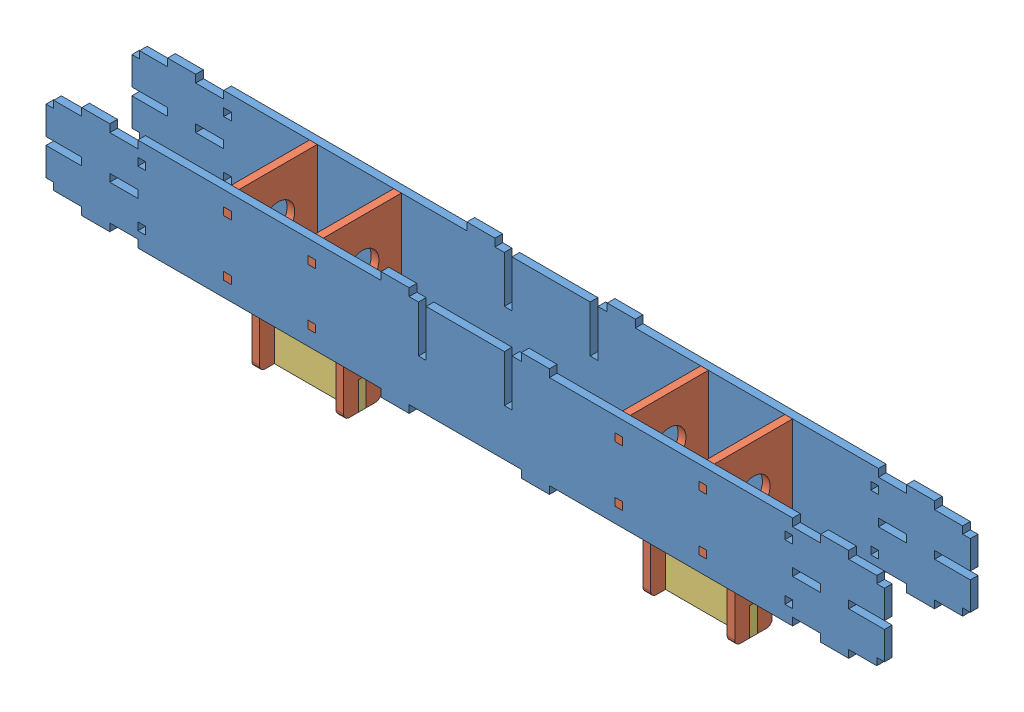
SolidWorks assembly ArmAssembly, configuration Default. Lengths in mm.
Overall size (448.2 94.1 50).
10 component instances, 3 part files, 9 mates.
Components (placement in the parent):
- sides-1: sides [Default] at origin size (448.2 58.2 4.1)
- sides-2: sides [Default] at (0 0 45.9) size (448.2 58.2 4.1)
- legAssembly-1: legAssembly [Default] at (-128.3412 -30.0492 25) x (0 -1 0) z (0 0 1) size (90 49.1 50)
  - rib-1: rib [Default] at (-55.0492 -0.7588 20.9) size (90 4.1 50)
  - rib-2: rib [Default] at (-55.0492 44.2412 20.9) size (90 4.1 50)
  - legBrace-1: legBrace [Default] at (19.9508 48.3412 -2.05) x (0 -1 0) z (-1 0 0) size (49.1 4.1 25)
- legAssembly-3: legAssembly [Default] at (80.7588 -30.0492 25) x (0 -1 0) z (0 0 1) size (90 49.1 50)
  - rib-1: rib [Default] at (-55.0492 -0.7588 20.9) size (90 4.1 50)
  - rib-2: rib [Default] at (-55.0492 44.2412 20.9) size (90 4.1 50)
  - legBrace-1: legBrace [Default] at (19.9508 48.3412 -2.05) x (0 -1 0) z (-1 0 0) size (49.1 4.1 25)
Mates (geometry in assembly coordinates):
- Coincident25: coincident: plane of sides-2 through (-80 -351.6861 122.6807) normal (-1 0 0); plane of legAssembly-1/rib-2 through (-80 17 45.9) normal (1 0 0)
- Coincident26: coincident: plane of sides-2 through (0 17 122.6807) normal (0 -1 0); plane of legAssembly-1/rib-2 through (-80 17 45.9) normal (0 1 0)
- Coincident29: coincident aligned: plane of sides-1 through (0 -351.6861 0) normal (0 0 -1); plane of legAssembly-1/rib-1 through (-125 17 0) normal (0 0 -1)
- Coincident30: coincident anti-aligned: plane of sides-1 through (-129.1 -351.6861 4.1) normal (1 0 0); plane of legAssembly-1/rib-1 through (-129.1 17 45.9) normal (-1 0 0)
- Coincident31: coincident anti-aligned: plane of sides-1 through (0 17 4.1) normal (0 -1 0); plane of legAssembly-1/rib-1 through (-125 17 4.1) normal (0 1 0)
- Coincident33: coincident anti-aligned: plane of sides-2 through (0 -351.6861 45.9) normal (0 0 -1); plane of legAssembly-1/rib-1 through (-125 12.9 45.9) normal (0 0 1)
- Coincident34: coincident: plane of sides-2 through (0 -351.6861 45.9) normal (0 0 -1); plane of legAssembly-3/rib-1 through (84.1 12.9 45.9) normal (0 0 1)
- Coincident35: coincident: plane of sides-2 through (0 17 50) normal (0 -1 0); plane of legAssembly-3/rib-2 through (129.1 17 45.9) normal (0 1 0)
- Coincident36: coincident anti-aligned: plane of sides-2 through (129.1 -351.6861 50) normal (-1 0 0); plane of legAssembly-3/rib-2 through (129.1 17 45.9) normal (1 0 0)
